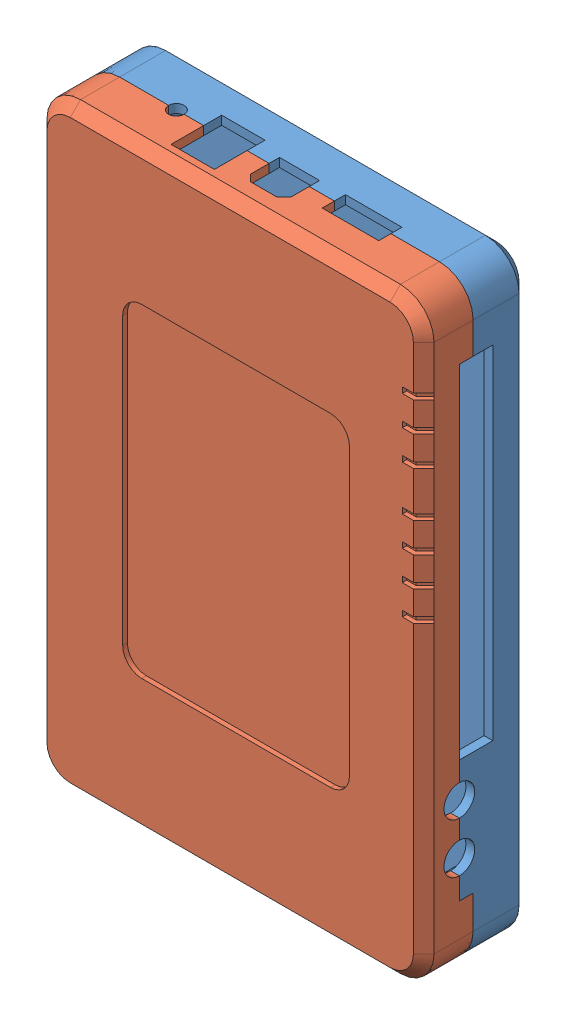
SolidWorks assembly myRIO, configuration 預設. Lengths in mm.
Overall size (88.6 136.6 24.18).
2 component instances, 2 part files, 6 mates.
Components (placement in the parent):
- myRIO Bottom-1: myRIO Bottom [預設] at (0 0 12.88) x (-1 0 0) z (0 0 -1) size (88.6 136.6 16.04)
- myRIO Top-1: myRIO Top [預設] at (0 0 12.88) size (88.6 136.6 11.3)
Mates (geometry in assembly coordinates):
- 重合/共線/共點1: coincident: plane of myRIO Bottom-1 through (36.6 60.6 12.88) normal (0 0 1); plane of myRIO Top-1 through (-36.6 60.6 12.88) normal (0 0 -1)
- 重合/共線/共點2: coincident: plane of myRIO Bottom-1 through (44.3 60.6 0) normal (1 0 0); plane of myRIO Top-1 through (44.3 60.6 24.18) normal (1 0 0)
- 重合/共線/共點3: coincident: plane of myRIO Bottom-1 through (-36.6 68.3 0) normal (0 1 0); plane of myRIO Top-1 through (-36.6 68.3 24.18) normal (0 1 0)
- 相互對稱1: symmetric: plane of myRIO Bottom-1 through (-44.3 -60.6 0) normal (-1 0 0); plane of myRIO Bottom-1 through (44.3 60.6 0) normal (1 0 0); plane of assembly
- 重合/共線/共點5: coincident: plane of myRIO Bottom-1 through (36.6 60.6 0) normal (0 0 -1); plane of assembly through (0 0 0) normal (0 0 1)
- 相互對稱4: symmetric: plane of myRIO Bottom-1 through (-36.6 68.3 0) normal (0 1 0); plane of myRIO Bottom-1 through (36.6 -68.3 0) normal (0 -1 0); plane of assembly
